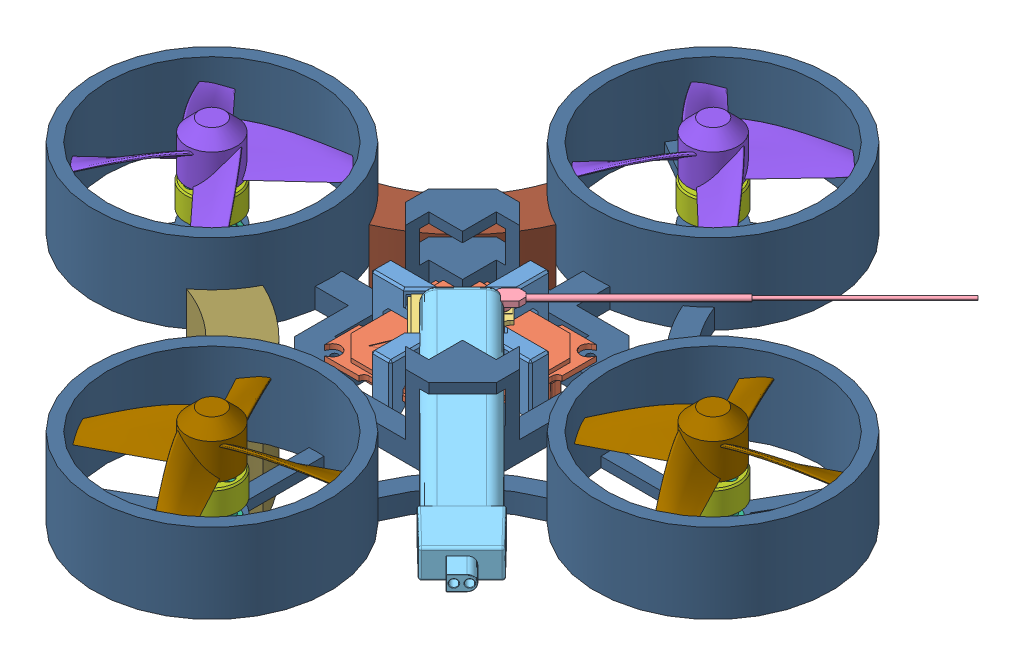
SolidWorks assembly BrushlessWhoopExternalRX_BetaFPV, configuration Default. Lengths in mm.
Overall size (166.86 36.3 166.86).
30 component instances, 12 part files, 47 mates.
Components (placement in the parent):
- Assem5^BrushlessWhoopExternalRX_BetaFPV-1: Assem5^BrushlessWhoopExternalRX_BetaFPV [Default] at (-4.6231 -8 63.8999) size (71.67 13.87 71.67) (virtual)
  - BoardClip-1: BoardClip [Default] at (0 11 0) size (32 10 32)
  - FlightControllerNoRX-1: FlightControllerNoRX [Default] at (0 8.5 0) x (-1 0 0) z (0 0 -1) size (31.11 6.8 31.11)
  - Receiver-1: Receiver [Default] at (-0.5303 14.025 0.5303) x (-0.707107 0 -0.707107) z (0.707107 0 -0.707107) size (10.9 4.12 80.79)
    - ReceiverChip-1: ReceiverChip [Default] at origin size (10.9 2.97 15.1)
    - ReceiverAntenna-1: ReceiverAntenna [Default] at (2.55 1.695 7.785) x (0 0 -1) z (1 0 0) size (68.5 2.1 3.15)
- Battery_BT2-2: Battery_BT2 [Default] at (11.8796 6.85 80.154) x (0.707107 0 -0.707107) z (0.707107 0 0.707107) size (12.7 6.25 69.62)
- Assem1^BrushlessWhoopExternalRX_BetaFPV-1: Assem1^BrushlessWhoopExternalRX_BetaFPV [Default] at origin size (55.98 19.6 55.98) (virtual, flexible)
  - Motor-1: Motor [Default] at (-4.4255 -2 13.5073) x (-0.707107 0 0.707107) z (-0.707107 0 -0.707107) size (14.75 14.8 14.75) (flexible)
    - Motor_Coils-1: Motor_Coils [Default] at origin size (8.75 6.11 9.61)
    - Motor_Bell-1: Motor_Bell [Default] at (0 4.8 0) x (0.025124 0 0.999684) z (-0.999684 0 0.025124) size (10.5 14.8 10.5)
  - Prop_CCW-1: Prop_CCW [Default] at (-4.4255 7.7 13.5073) x (-0.724649 0 -0.689119) z (0.689119 0 -0.724649) size (40.23 9.6 40.23)
- Assem2^BrushlessWhoopExternalRX_BetaFPV-1: Assem2^BrushlessWhoopExternalRX_BetaFPV [Default] at (0.2125 -0.0698 10.3695) size (54.61 19.6 54.61) (virtual, flexible)
  - Motor-1: Motor [Default] at (-54.8356 -1.9302 53.3354) x (-0.258819 0 -0.965926) z (0.965926 0 -0.258819) size (14.75 14.8 14.75) (flexible)
    - Motor_Coils-1: Motor_Coils [Default] at origin size (8.75 6.11 9.61)
    - Motor_Bell-1: Motor_Bell [Default] at (0 4.8 0) x (-0.926411 0 0.376514) z (-0.376514 0 -0.926411) size (10.5 14.8 10.5)
  - Prop_CCW-1: Prop_CCW [Default] at (-54.8356 7.7698 53.3354) x (0.677572 0 0.735457) z (-0.735457 0 0.677572) size (40.23 9.6 40.23)
- Assem3^BrushlessWhoopExternalRX_BetaFPV-1: Assem3^BrushlessWhoopExternalRX_BetaFPV [Default] at (-100.3827 22.9027 142.0107) size (47.09 19.6 47.09) (virtual, flexible)
  - Motor-1: Motor [Default] at (95.9546 -24.9027 -28.1108) x (0.258819 0 0.965926) z (-0.965926 0 0.258819) size (14.75 14.8 14.75) (flexible)
    - Motor_Coils-1: Motor_Coils [Default] at origin size (8.75 6.11 9.61)
    - Motor_Bell-1: Motor_Bell [Default] at (0 4.8 0) x (0.553159 0 -0.833075) z (0.833075 0 0.553159) size (10.5 14.8 10.5)
  - Prop_CW-1: Prop_CW [Default] at (95.9546 -15.2027 -28.1108) x (-0.470178 0 -0.882572) z (0.882572 0 -0.470178) size (40.23 9.6 40.23)
- Assem4^BrushlessWhoopExternalRX_BetaFPV-1: Assem4^BrushlessWhoopExternalRX_BetaFPV [Default] at (-0.1388 -0.0749 10.724) size (50.83 19.6 50.83) (virtual, flexible)
  - Motor-1: Motor [Default] at (45.9083 -1.9251 52.9783) x (0.707107 0 -0.707107) z (0.707107 0 0.707107) size (14.75 14.8 14.75) (flexible)
    - Motor_Coils-1: Motor_Coils [Default] at origin size (8.75 6.11 9.61)
    - Motor_Bell-1: Motor_Bell [Default] at (0 4.8 0) x (-0.901934 0 -0.431873) z (0.431873 0 -0.901934) size (10.5 14.8 10.5)
  - Prop_CW-1: Prop_CW [Default] at (45.9083 7.7749 52.9783) x (0.459716 0 0.888066) z (-0.888066 0 0.459716) size (40.23 9.6 40.23)
- chassis-1: chassis [Default] at (-4.4268 -4 63.7036) x (-0.707107 0 -0.707107) z (0.707107 0 -0.707107) size (117.99 16.2 117.99)
- LandingFeet2-1: LandingFeet2 [Default] at (-4.4268 0 63.7036) x (-0.707107 0 -0.707107) z (0 1 0) size (12.68 26.44 23)
- LandingFeet2_Battery-1: LandingFeet2_Battery [Default] at (-4.4268 0 63.7036) x (-0.707107 0 -0.707107) z (0 1 0) size (26.26 13.11 23)
Mates (geometry in assembly coordinates):
- Coincident1: coordinate: point of 40mmDuctCustom_Strong_Brushless-1
- Coincident4: coincident anti-aligned: plane of 40mmDuctCustom_Strong_Brushless-1 through (-17.5163 0 0) normal (0 -1 0); plane of BatteryClip-1 through (-1.2374 0 14.3189) normal (0 1 0)
- Parallel3: parallel aligned: plane of 40mmDuctCustom_Strong_Brushless-1 through (0 0 0) normal (0.707107 0 -0.707107); plane of BatteryClip-1 through (-5.6569 0 5.6569) normal (0.707107 0 -0.707107)
- Coincident6: coincident anti-aligned: plane of Hood-1 through (0 9 0) normal (-1 0 0)
- Coincident7: coincident anti-aligned: plane of Hood-1 through (0 9 0) normal (0 0 -1)
- Width1: width: plane of 40mmDuctCustom_Strong_Brushless-1 through (-52.1259 0 19.1737) normal (-0.866025 0 -0.5); plane of Leg-1 through (-50.2992 5 19.2097) normal (0.866025 0 0.5); plane of 40mmDuctCustom_Strong_Brushless-1 through (-47.6453 0 14.763) normal (-0.866025 0 -0.5); plane of Leg-1 through (-49.1608 5.25 13.888) normal (0.866025 0 0.5)
- Coincident10: coincident anti-aligned: plane of 40mmDuctCustom_Strong_Brushless-1 through (-17.5163 0 0) normal (0 -1 0); plane of Leg-1 through (-49.1608 0 13.888) normal (0 1 0)
- Concentric1: concentric aligned: circle of 40mmDuctCustom_Strong_Brushless-1; cylinder of Leg-1 through (-40.1322 1.8061 0) axis (0 1 0) radius 23.82
- Concentric20: concentric anti-aligned: cylinder of 40mmDuctCustom_Strong_Brushless-1 through (0 -0.0013 36.6681) axis (0 1 0) radius 1; cylinder of Assem1^BrushlessWhoopExternalRX_BetaFPV-1/Motor-1/Motor_Coils-1 through (-7.7716 -1 14.4038) axis (0 -1 0) radius 0.625
- Concentric21: concentric anti-aligned: cylinder of 40mmDuctCustom_Strong_Brushless-1 through (3 -0.0013 41.8643) axis (0 1 0) radius 1; cylinder of Assem1^BrushlessWhoopExternalRX_BetaFPV-1/Motor-1/Motor_Coils-1 through (-3.5289 -1 10.1612) axis (0 -1 0) radius 0.625
- Coincident26: coincident anti-aligned: plane of 40mmDuctCustom_Strong_Brushless-1 through (0 2 40.1322) normal (0 1 0); plane of Assem1^BrushlessWhoopExternalRX_BetaFPV-1/Motor-1/Motor_Coils-1 through (-4.2968 -2 18.8224) normal (0 -1 0)
- Concentric22: concentric anti-aligned: cylinder of 40mmDuctCustom_Strong_Brushless-1 through (0 -0.0013 -36.6681) axis (0 1 0) radius 1; cylinder of Assem2^BrushlessWhoopExternalRX_BetaFPV-1/Motor-1/Motor_Coils-1 through (-53.7265 -1 60.3588) axis (0 -1 0) radius 0.625
- Concentric23: concentric anti-aligned: cylinder of 40mmDuctCustom_Strong_Brushless-1 through (-3 -0.0013 -41.8643) axis (0 1 0) radius 1; cylinder of Assem2^BrushlessWhoopExternalRX_BetaFPV-1/Motor-1/Motor_Coils-1 through (-52.1736 -1 66.1544) axis (0 -1 0) radius 0.625
- Coincident27: coincident anti-aligned: plane of 40mmDuctCustom_Strong_Brushless-1 through (0 2 -40.1322) normal (0 1 0); plane of Assem2^BrushlessWhoopExternalRX_BetaFPV-1/Motor-1/Motor_Coils-1 through (-59.2905 -2 61.1588) normal (0 -1 0)
- Concentric24: concentric anti-aligned: cylinder of 40mmDuctCustom_Strong_Brushless-1 through (41.8643 -0.0013 3) axis (0 1 0) radius 1; cylinder of Assem3^BrushlessWhoopExternalRX_BetaFPV-1/Motor-1/Motor_Coils-1 through (-5.3247 -1 117.246) axis (0 -1 0) radius 0.625
- Concentric25: concentric anti-aligned: cylinder of 40mmDuctCustom_Strong_Brushless-1 through (36.6681 -0.0013 0) axis (0 1 0) radius 1; cylinder of Assem3^BrushlessWhoopExternalRX_BetaFPV-1/Motor-1/Motor_Coils-1 through (-6.8776 -1 111.4504) axis (0 -1 0) radius 0.625
- Coincident28: coincident anti-aligned: plane of 40mmDuctCustom_Strong_Brushless-1 through (40.1322 2 0) normal (0 1 0); plane of Assem3^BrushlessWhoopExternalRX_BetaFPV-1/Motor-1/Motor_Coils-1 through (0.2393 -2 116.446) normal (0 -1 0)
- Concentric26: concentric anti-aligned: cylinder of 40mmDuctCustom_Strong_Brushless-1 through (-41.8643 -0.0013 -3) axis (0 1 0) radius 1; cylinder of Assem4^BrushlessWhoopExternalRX_BetaFPV-1/Motor-1/Motor_Coils-1 through (49.1156 -1 62.8057) axis (0 -1 0) radius 0.625
- Concentric27: concentric anti-aligned: cylinder of 40mmDuctCustom_Strong_Brushless-1 through (-36.6681 -0.0013 0) axis (0 1 0) radius 1; cylinder of Assem4^BrushlessWhoopExternalRX_BetaFPV-1/Motor-1/Motor_Coils-1 through (44.8729 -1 67.0483) axis (0 -1 0) radius 0.625
- Coincident29: coincident anti-aligned: plane of 40mmDuctCustom_Strong_Brushless-1 through (-40.1322 2 0) normal (0 1 0); plane of Assem4^BrushlessWhoopExternalRX_BetaFPV-1/Motor-1/Motor_Coils-1 through (45.6408 -2 58.3872) normal (0 -1 0)
- Parallel4: parallel aligned: plane of Assem5^BrushlessWhoopExternalRX_BetaFPV-1/BoardClip-1 through (-2.6231 8 47.8999) normal (1 0 0)
- Parallel5: parallel aligned: plane of Assem5^BrushlessWhoopExternalRX_BetaFPV-1/BoardClip-1 through (11.3769 8 65.8999) normal (0 0 1)
- Coincident52: coincident anti-aligned: plane of Battery_BT2-2 through (28.8501 3.85 102.0743) normal (0 -1 0); plane of chassis-1 through (-17.9339 3.85 41.5724) normal (0 1 0)
- Coincident53: coincident anti-aligned: plane of Battery_BT2-2 through (27.0824 6.35 103.8421) normal (-0.707107 0 0.707107); plane of chassis-1 through (-26.5606 3.85 50.1991) normal (0.707107 0 -0.707107)
- Coincident54: coincident anti-aligned: plane of Assem1^BrushlessWhoopExternalRX_BetaFPV-1/Motor-1/Motor_Coils-1 through (-4.2968 -2 18.8224) normal (0 -1 0); plane of chassis-1 through (-4.4268 -2 63.7036) normal (0 1 0)
- Coincident55: coincident aligned: circle of Assem1^BrushlessWhoopExternalRX_BetaFPV-1/Motor-1/Motor_Coils-1; circle of chassis-1
- Coincident57: coincident aligned: circle of Assem1^BrushlessWhoopExternalRX_BetaFPV-1/Motor-1/Motor_Coils-1; circle of chassis-1
- Coincident58: coincident anti-aligned: plane of Assem4^BrushlessWhoopExternalRX_BetaFPV-1/Motor-1/Motor_Coils-1 through (45.6408 -2 58.3872) normal (0 -1 0); plane of chassis-1 through (-4.4268 -2 63.7036) normal (0 1 0)
- Concentric28: concentric aligned: cylinder of Assem4^BrushlessWhoopExternalRX_BetaFPV-1/Motor-1/Motor_Coils-1 through (49.1156 -1 62.8057) axis (0 -1 0) radius 0.625; cylinder of chassis-1 through (49.1156 -2 62.8057) axis (0 -1 0) radius 0.625
- Concentric29: concentric aligned: cylinder of Assem4^BrushlessWhoopExternalRX_BetaFPV-1/Motor-1/Motor_Coils-1 through (43.32 -1 61.2528) axis (0 -1 0) radius 0.625; cylinder of chassis-1 through (43.32 -2 61.2528) axis (0 -1 0) radius 0.625
- Coincident59: coincident anti-aligned: plane of Assem2^BrushlessWhoopExternalRX_BetaFPV-1/Motor-1/Motor_Coils-1 through (-59.2905 -2 61.1588) normal (0 -1 0); plane of chassis-1 through (-4.4268 -2 63.7036) normal (0 1 0)
- Concentric30: concentric aligned: cylinder of Assem2^BrushlessWhoopExternalRX_BetaFPV-1/Motor-1/Motor_Coils-1 through (-57.9692 -1 64.6015) axis (0 -1 0) radius 0.625; cylinder of chassis-1 through (-57.9692 -2 64.6015) axis (0 -1 0) radius 0.625
- Concentric31: concentric aligned: cylinder of Assem2^BrushlessWhoopExternalRX_BetaFPV-1/Motor-1/Motor_Coils-1 through (-53.7265 -1 60.3588) axis (0 -1 0) radius 0.625; cylinder of chassis-1 through (-53.7265 -2 60.3588) axis (0 -1 0) radius 0.625
- Coincident60: coincident anti-aligned: plane of Assem3^BrushlessWhoopExternalRX_BetaFPV-1/Motor-1/Motor_Coils-1 through (0.2393 -2 116.446) normal (0 -1 0); plane of chassis-1 through (-4.4268 -2 63.7036) normal (0 1 0)
- Concentric32: concentric aligned: cylinder of Assem3^BrushlessWhoopExternalRX_BetaFPV-1/Motor-1/Motor_Coils-1 through (-1.0821 -1 113.0033) axis (0 -1 0) radius 0.625; cylinder of chassis-1 through (-1.0821 -2 113.0033) axis (0 -1 0) radius 0.625
- Concentric33: concentric aligned: cylinder of Assem3^BrushlessWhoopExternalRX_BetaFPV-1/Motor-1/Motor_Coils-1 through (-5.3247 -1 117.246) axis (0 -1 0) radius 0.625; cylinder of chassis-1 through (-5.3247 -2 117.246) axis (0 -1 0) radius 0.625
- Coincident61: coincident anti-aligned: plane of Assem5^BrushlessWhoopExternalRX_BetaFPV-1/BoardClip-1 through (-20.6231 8 65.8999) normal (-1 0 0); plane of chassis-1 through (-20.6231 0 63.7036) normal (1 0 0)
- Coincident62: coincident anti-aligned: plane of Assem5^BrushlessWhoopExternalRX_BetaFPV-1/BoardClip-1 through (-2.6231 8 79.8999) normal (0 0 1); plane of chassis-1 through (-4.4268 0 79.8999) normal (0 0 -1)
- Coincident63: coincident anti-aligned: plane of Assem5^BrushlessWhoopExternalRX_BetaFPV-1/FlightControllerNoRX-1 through (-4.6231 0 63.8999) normal (0 -1 0); plane of chassis-1 through (-4.4268 0 63.7036) normal (0 1 0)
- InPlace3: in place: plane of ? through (-4.4268 40.9867 63.7036) normal (0 1 0); plane of ? through (0 40.9867 0) normal (0 1 0); moOrthogonalPlaneRef_w of ? through (-4.4268 40.9867 63.7036) normal (0 1 0); plane of ? through (0 40.9867 0) normal (0 0 -1); plane of ? through (-4.4268 40.9867 63.7036) normal (0 1 0); plane of ? through (0 40.9867 0) normal (1 0 0); plane of chassis-1 through (-4.4268 0 63.7036) normal (0 1 0); unknown of ?
- Coincident64: coincident aligned: plane of ?; plane of ?
- Coincident65: coincident aligned: moOrthogonalPlaneRef_w of chassis-1 through (-4.4268 0 63.7036) normal (-0.707107 0 0.707107); plane of Part1^BrushlessWhoopExternalRX_BetaFPV-1 through (-4.4268 0 63.7036) normal (-0.707107 0 0.707107)
- Coincident66: coincident anti-aligned: moOrthogonalPlaneRef_w of chassis-1 through (-4.4268 0 63.7036) normal (0.707107 0 0.707107); plane of Part1^BrushlessWhoopExternalRX_BetaFPV-1 through (-4.4268 0 63.7036) normal (-0.707107 0 -0.707107)
- InPlace5: in place: plane of chassis-1 through (-4.4268 0 63.7036) normal (0 1 0); plane of ? through (0 0 0) normal (0 1 0); plane of chassis-1 through (-4.4268 0 63.7036) normal (0 1 0); plane of ? through (0 0 0) normal (0 0 -1); plane of chassis-1 through (-4.4268 0 63.7036) normal (0 1 0); plane of ? through (0 0 0) normal (1 0 0); plane of chassis-1 through (-4.4268 0 63.7036) normal (0 1 0); unknown of ?
- Coincident67: coincident aligned: plane of ?; plane of ?
- Coincident68: coincident aligned: moOrthogonalPlaneRef_w of chassis-1 through (-4.4268 0 63.7036) normal (-0.707107 0 0.707107); plane of Part4^BrushlessWhoopExternalRX_BetaFPV-1 through (-4.4268 0 63.7036) normal (-0.707107 0 0.707107)
- Coincident69: coincident anti-aligned: moOrthogonalPlaneRef_w of chassis-1 through (-4.4268 0 63.7036) normal (0.707107 0 0.707107); plane of Part4^BrushlessWhoopExternalRX_BetaFPV-1 through (-4.4268 0 63.7036) normal (-0.707107 0 -0.707107)
